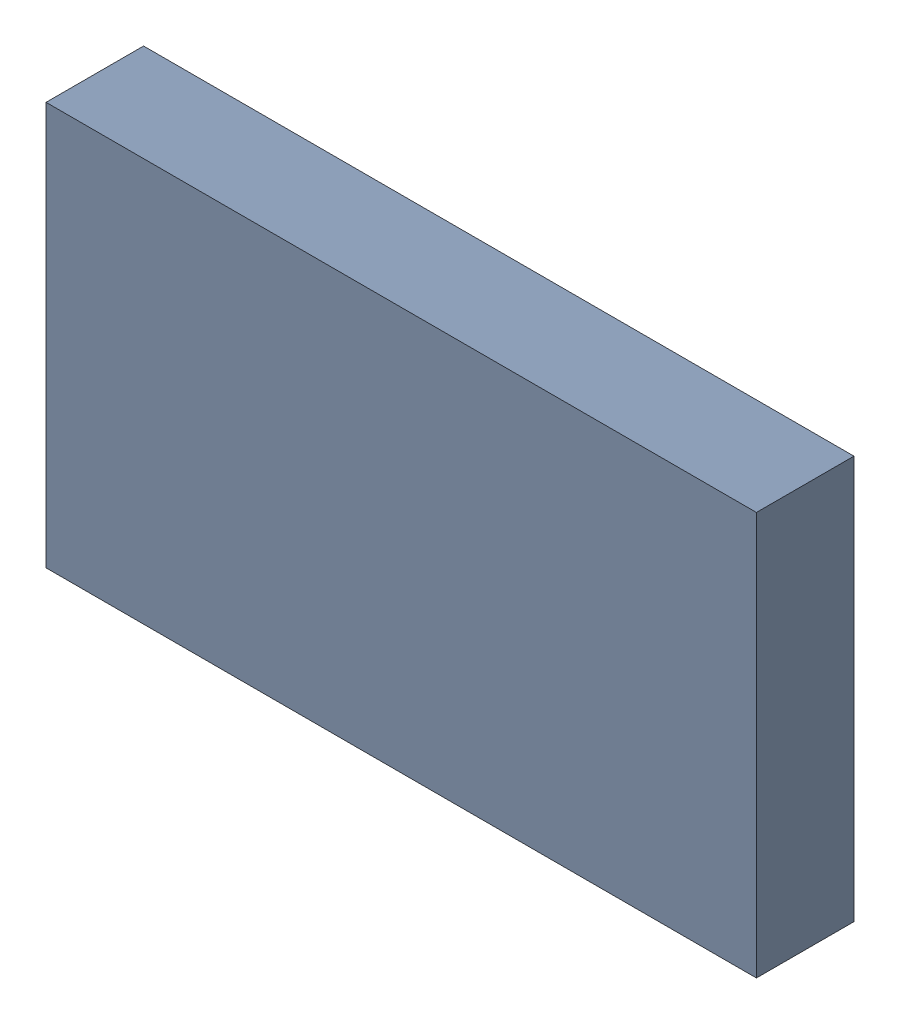
SolidWorks assembly 6327399424, configuration Default. Lengths in mm.
Overall size (1.85 1.05 0.25).
2 component instances, 1 part files, 0 mates.
Components (placement in the parent):
- 6701982208-1:  [Default] at (27.7 14.8 0) (suppressed, hidden)
- Extruded-9-1: Extruded-9 [Default] at origin size (1.85 1.05 0.25)
